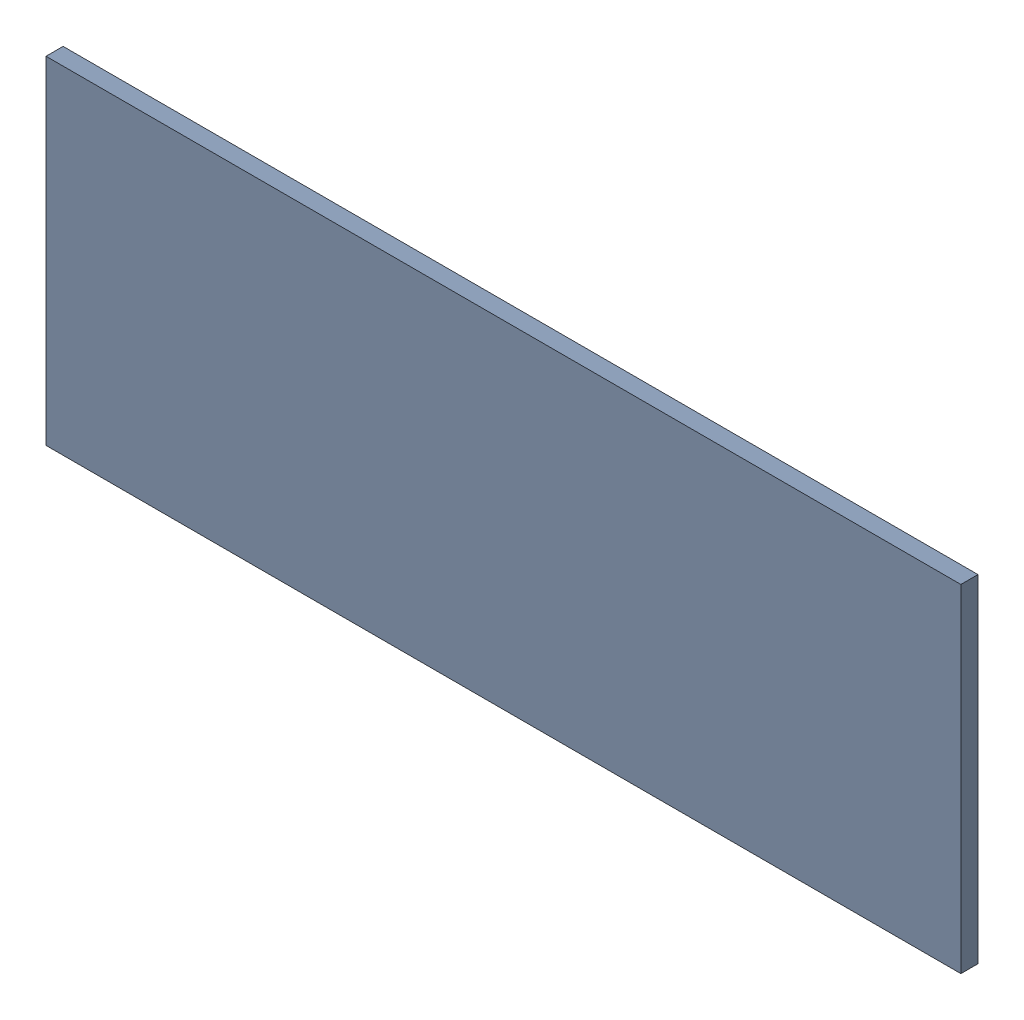
SolidWorks assembly Pad RAK4600-3(14.5mm,25mm) on Top Layer, configuration Predeterminado. Lengths in mm.
Overall size (1.9 0.7 0.04).
2 component instances, 1 part files, 0 mates.
Components (placement in the parent):
- Pad RAK4600-3(14.5mm,25mm) on Top Layer-1-1: Pad RAK4600-3(14.5mm,25mm) on Top Layer-1 [Predeterminado] at (-68.317 -44.187 -0.0457) size (1.9 0.7 0.04)
  - Pad RAK4600-3(14.5mm,25mm) on Top Layer-Part-1-1: Pad RAK4600-3(14.5mm,25mm) on Top Layer-Part-1 [Predeterminado] at origin size (1.9 0.7 0.04)
